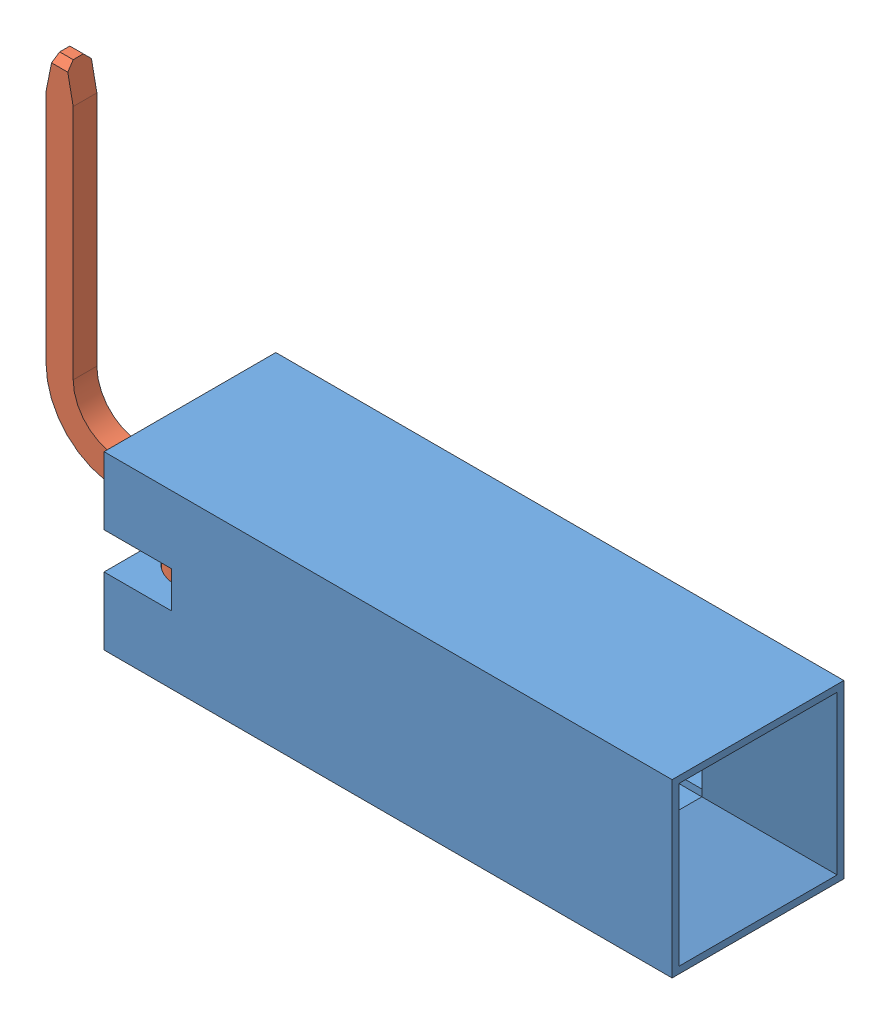
SolidWorks assembly FrameAndPin_H254_90deg, configuration Default. Lengths in mm.
Overall size (10.36 6.14 2.54).
2 component instances, 2 part files, 2 mates.
Components (placement in the parent):
- frame_H254-1: frame_H254 [Default] at origin size (8.4 2.54 2.54)
- pin-90deg-1: pin-90deg [Default] at (-0.0461 1.2682 1.27) x (0 0 -1) z (0.999998 -0.002105 0) size (1.95 5.07 7.58)
Mates (geometry in assembly coordinates):
- Distance3: distance = 1.095 mm: plane of assembly; plane of assembly; plane of pin-90deg-1 through (-3.2461 1.07 1.445) normal (0 0 1); plane of frame_H254-1 through (0 0 2.54) normal (0 0 1)
- Distance4: distance = 1.07 mm: plane of assembly; plane of assembly; plane of pin-90deg-1 through (5.5157 1.47 1.9307) normal (0 1 0); plane of frame_H254-1 through (0 2.54 2.54) normal (0 1 0)
